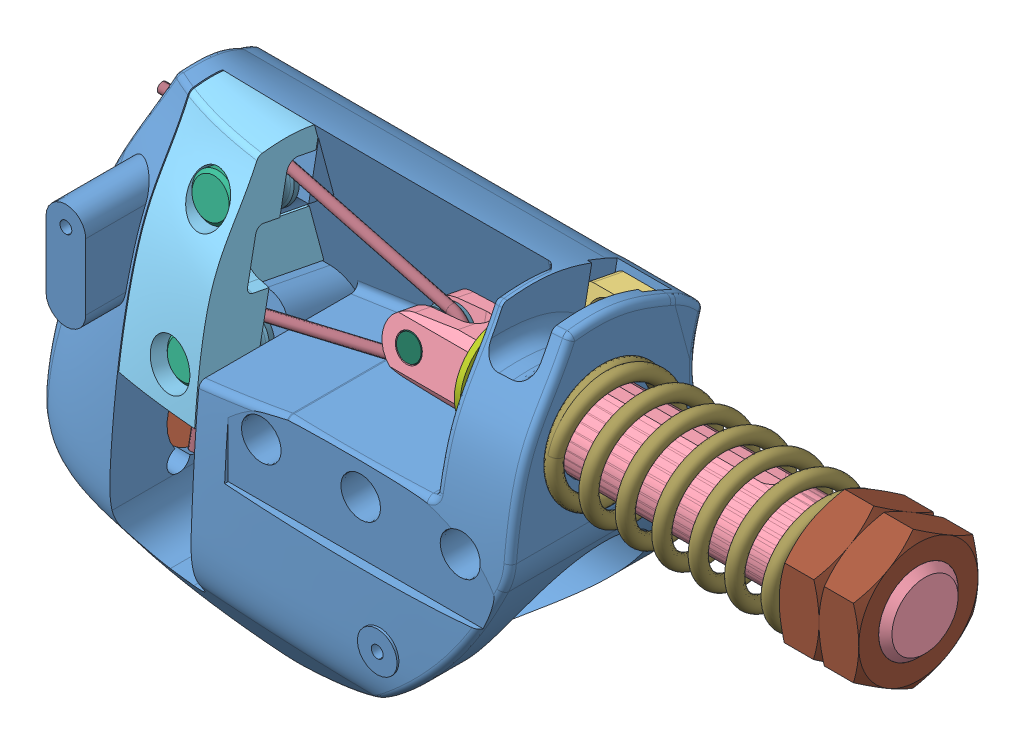
SolidWorks assembly a-motorträger-beine-links-v01, configuration 01. Lengths in mm.
Overall size (130.38 65.2 41.74).
22 component instances, 15 part files, 71 mates.
Components (placement in the parent):
- p-halterreferenz-links-v04-1: p-halterreferenz-links-v04 [01] at (-8 0 0) x (0 0 -1) z (1 0 0) size (41.74 65.2 84.36)
- z-jfm-0608-06-v01-1: z-jfm-0608-06-v01 [01] at (-23.3 0 0) x (-1 0 0) z (0 0 -1) size (6 12 12)
- z-induktiv-sensor-v01-1: z-induktiv-sensor-v01 [01] at (37 21.9082 -7.6275) x (-1 0 0) z (0 0.190809 0.981627) size (8 16 4.7)
- z-induktiv-sensor-v01-2: z-induktiv-sensor-v01 [01] at (-25.5 8.63 4) x (0 0 -1) z (-1 0 0) size (8 16 4.7)
- p-federstössel-v01-1: p-federstössel-v01 [01] at (77.9 27.8 1.72) x (-1 0 0) z (0 -0.190809 -0.981627) size (77 12 12)
- p-halterdeckel-links-v02-1: p-halterdeckel-links-v02 [01] at (-8 0 0) x (0 0 -1) z (1 0 0) size (28.27 33.45 14.71)
- z-passschraube-misumi-4-v01-1: z-passschraube-misumi-4-v01 [01] at (-13.1 35.2829 8.5672) x (0 -0.190809 -0.981627) z (-0.839411 0.533511 -0.103704) size (18 6.5 6.5)
- z-passschraube-misumi-4-v01-2: z-passschraube-misumi-4-v01 [01] at (-13.1 16.1412 12.288) x (0 -0.190809 -0.981627) z (-0.58333 -0.797312 0.154982) size (18 6.5 6.5)
- Lock washer DIN 6799 - 7-8: Lock washer DIN 6799 - 7 [Lock washer DIN 6799 - 7] at (24 27.8 1.72) x (0 0 1) z (-1 0 0) size (14.3 11.94 0.9)
- Hexagon Nut ISO 4032 - M2.5 - W - N-13: Hexagon Nut ISO 4032 - M2.5 - W - N [Hexagon Nut ISO 4032 - M2.5 - W - N] at (-13.1 31.8991 -8.8409) x (0.5 0.850114 -0.165245) z (0 -0.190809 -0.981627) size (5 5.77 2)
- Hexagon Nut ISO 4032 - M2.5 - W - N-14: Hexagon Nut ISO 4032 - M2.5 - W - N [Hexagon Nut ISO 4032 - M2.5 - W - N] at (-13.1 12.7574 -5.1202) x (0.5 0.850114 -0.165245) z (0 -0.190809 -0.981627) size (5 5.77 2)
- DIN 7991 - M3 x 8 --- 4.8C-13: DIN 7991 - M3 x 8 --- 4.8C [DIN 7991 - M3 x 8 --- 4.8C] at (-30.15 20.63 0) size (8 5.7 5.7)
- DIN 7991 - M3 x 8 --- 4.8C-14: DIN 7991 - M3 x 8 --- 4.8C [DIN 7991 - M3 x 8 --- 4.8C] at (33 34.5749 -5.3527) x (0 -0.190809 -0.981627) z (-0.981627 -0.187303 0.036408) size (8 5.7 5.7)
- p-oese-v01-1: p-oese-v01 [01] at (-25.5 37.4 0) size (3.5 4 4)
- Hexagon Thin Nut ISO 4035 - M12 - N-13: Hexagon Thin Nut ISO 4035 - M12 - N [Hexagon Thin Nut ISO 4035 - M12 - N] at (74.9 27.8 1.72) x (0 -0.006521 -0.999979) z (-1 0 0) size (18 20.78 6)
- Hexagon Thin Nut ISO 4035 - M12 - N-14: Hexagon Thin Nut ISO 4035 - M12 - N [Hexagon Thin Nut ISO 4035 - M12 - N] at (80.9 27.8 1.72) x (0 0 1) z (-1 0 0) size (18 20.78 6)
- z-feder-febrotec-v01-1: z-feder-febrotec-v01 [01] at (40 27.5466 1.7693) x (1 0 0) z (0 -0.190809 -0.981627) size (40.25 20.98 20.5)
- p-seil-v02-1: p-seil-v02 [01] at (-16.85 -0.1381 7.1506) x (-1 0 0) z (0 -0.190809 -0.981627) size (48.5 39 1.5)
- p-umlenkpulley-v06-1: p-umlenkpulley-v06 [01] at (-13.1 33.728 0.5677) x (0 -0.190809 -0.981627) z (-0.981627 -0.187303 0.036408) size (3.6 7.15 7.15)
- p-umlenkpulley-v06-4: p-umlenkpulley-v06 [01] at (-13.1 14.5863 4.2885) x (0 -0.190809 -0.981627) z (-0.997632 -0.067518 0.013124) size (3.6 7.15 7.15)
- p-umlenkpulley-v06-3: p-umlenkpulley-v06 [01] at (14.9 27.8 1.72) x (0 -0.190809 -0.981627) z (-0.981627 -0.187303 0.036408) size (3.6 7.15 7.15)
- Parallel Pin ISO 2338 - 4 h6 x 10 - St-8: Parallel Pin ISO 2338 - 4 h6 x 10 - St [Parallel Pin ISO 2338 - 4 h6 x 10 - St] at (14.9 28.754 6.6281) x (0 -0.190809 -0.981627) z (-0.981627 -0.187303 0.036408) size (10 4 4)
Mates (geometry in assembly coordinates):
- Deckungsgleich4: coincident anti-aligned: plane of z-jfm-0608-06-v01-1 through (-23.3 0 0) normal (0 0 -1); plane of assembly through (0 0 0) normal (0 0 1)
- Deckungsgleich22: coincident aligned: plane of p-halterreferenz-links-v04-1; plane of assembly through (0 0 0) normal (0 1 0)
- Deckungsgleich23: coincident anti-aligned: plane of p-halterreferenz-links-v04-1 through (-8 0 0) normal (0 0 -1); plane of assembly through (0 0 0) normal (0 0 1)
- Konzentrisch3: concentric aligned: cylinder of z-induktiv-sensor-v01-2 through (-30.2 20.63 0) axis (-1 0 0) radius 1.55; cylinder of p-halterreferenz-links-v04-1 through (38.3169 20.63 0) axis (-1 0 0) radius 1.23
- Deckungsgleich25: coincident aligned: plane of z-induktiv-sensor-v01-2; plane of p-halterreferenz-links-v04-1 through (-8 0 0) normal (0 0 -1)
- Deckungsgleich26: coincident anti-aligned: plane of z-induktiv-sensor-v01-2 through (-25.5 8.63 4) normal (1 0 0); plane of p-halterreferenz-links-v04-1 through (-25.5 0 0) normal (-1 0 0)
- Konzentrisch4: concentric aligned: cylinder of p-halterreferenz-links-v04-1 through (-39.3597 27.8 1.72) axis (1 0 0) radius 6.125; cylinder of p-federstössel-v01-1 through (77.9 27.8 1.72) axis (1 0 0) radius 6
- Parallel3: parallel anti-aligned: plane of p-halterreferenz-links-v04-1 through (-39.3597 33.8847 2.4219) normal (0 0.190809 0.981627); plane of p-federstössel-v01-1 through (65.9 35.5438 2.2522) normal (0 -0.190809 -0.981627)
- Deckungsgleich32: coincident aligned: plane of p-halterreferenz-links-v04-1; plane of p-halterdeckel-links-v02-1
- Deckungsgleich33: coincident anti-aligned: plane of p-halterdeckel-links-v02-1 through (-8 0 0) normal (0 0 -1); plane of assembly through (0 0 0) normal (0 0 1)
- Deckungsgleich34: coincident aligned: plane of p-halterdeckel-links-v02-1 through (-8 0 0) normal (1 0 0); plane of p-halterreferenz-links-v04-1 through (-8 0 0) normal (1 0 0)
- Konzentrisch5: concentric aligned: cylinder of p-halterreferenz-links-v04-1 through (-13.1 32.6624 -4.9144) axis (0 0.190809 0.981627) radius 2.075; cylinder of z-passschraube-misumi-4-v01-1 through (-13.1 35.2829 8.5672) axis (0 0.190809 0.981627) radius 2
- Deckungsgleich35: coincident anti-aligned: plane of p-halterdeckel-links-v02-1 through (-13.1 2.3168 11.919) normal (0 0.190809 0.981627); plane of z-passschraube-misumi-4-v01-1 through (-14.8664 32.0326 6.1429) normal (0 -0.190809 -0.981627)
- Konzentrisch7: concentric aligned: cylinder of p-halterreferenz-links-v04-1 through (-13.1 13.5207 -1.1937) axis (0 0.190809 0.981627) radius 2.075; cylinder of z-passschraube-misumi-4-v01-2 through (-13.1 16.1412 12.288) axis (0 0.190809 0.981627) radius 2
- Deckungsgleich36: coincident anti-aligned: plane of p-halterdeckel-links-v02-1 through (-13.1 2.3168 11.919) normal (0 0.190809 0.981627); plane of z-passschraube-misumi-4-v01-2 through (-10.4602 13.7078 9.7048) normal (0 -0.190809 -0.981627)
- Konzentrisch9: concentric anti-aligned: cylinder of p-federstössel-v01-1 through (77.9 27.8 1.72) axis (1 0 0) radius 3.5; cylinder of Lock washer DIN 6799 - 7-8 through (24.9 27.8 1.72) axis (-1 0 0) radius 3.5
- Deckungsgleich40: coincident anti-aligned: plane of p-federstössel-v01-1 through (24.9 33.6898 0.5751) normal (-1 0 0); plane of Lock washer DIN 6799 - 7-8 through (24.9 27.8 1.72) normal (1 0 0)
- Konzentrisch10: concentric anti-aligned: cylinder of p-halterreferenz-links-v04-1 through (-13.1 27.2158 -32.9346) axis (0 0.190809 0.981627) radius 1.5; cylinder of Hexagon Nut ISO 4032 - M2.5 - W - N-13 through (-13.1 32.2808 -6.8777) axis (0 -0.190809 -0.981627) radius 1.025
- Parallel4: parallel anti-aligned: plane of p-halterreferenz-links-v04-1 through (-10.5 25.7423 -32.6482) normal (-0.5 0.850114 -0.165245); plane of Hexagon Nut ISO 4032 - M2.5 - W - N-13 through (-10.6 30.8639 -6.6023) normal (0.5 -0.850114 0.165245)
- Deckungsgleich42: coincident anti-aligned: plane of p-halterreferenz-links-v04-1 through (-8 -0.1129 -0.581) normal (0 -0.190809 -0.981627); plane of Hexagon Nut ISO 4032 - M2.5 - W - N-13 through (-10.6 30.8639 -6.6023) normal (0 0.190809 0.981627)
- Konzentrisch11: concentric anti-aligned: cylinder of p-halterreferenz-links-v04-1 through (-13.1 8.0741 -29.2138) axis (0 0.190809 0.981627) radius 1.5; cylinder of Hexagon Nut ISO 4032 - M2.5 - W - N-14 through (-13.1 13.139 -3.1569) axis (0 -0.190809 -0.981627) radius 1.025
- Parallel5: parallel anti-aligned: plane of p-halterreferenz-links-v04-1 through (-10.5 6.6006 -28.9274) normal (-0.5 0.850114 -0.165245); plane of Hexagon Nut ISO 4032 - M2.5 - W - N-14 through (-10.6 11.7222 -2.8815) normal (0.5 -0.850114 0.165245)
- Deckungsgleich44: coincident anti-aligned: plane of p-halterreferenz-links-v04-1 through (-8 -0.1129 -0.581) normal (0 -0.190809 -0.981627); plane of Hexagon Nut ISO 4032 - M2.5 - W - N-14 through (-10.6 11.7222 -2.8815) normal (0 0.190809 0.981627)
- Konzentrisch12: concentric aligned: cylinder of z-induktiv-sensor-v01-2 through (-30.2 20.63 0) axis (-1 0 0) radius 1.55; cylinder of DIN 7991 - M3 x 8 --- 4.8C-13 through (-30.15 20.63 0) axis (-1 0 0) radius 1.5
- Deckungsgleich45: coincident aligned: cone of z-induktiv-sensor-v01-2 through (-28.5 20.63 0) axis (1 0 0); cone of DIN 7991 - M3 x 8 --- 4.8C-13 through (-29.8 20.63 0) axis (1 0 0)
- Konzentrisch14: concentric aligned: cylinder of z-induktiv-sensor-v01-1 through (33 34.5845 -5.3036) axis (0 0.190809 0.981627) radius 1.55; cylinder of DIN 7991 - M3 x 8 --- 4.8C-14 through (33 34.5749 -5.3527) axis (0 0.190809 0.981627) radius 1.5
- Deckungsgleich46: coincident aligned: cone of z-induktiv-sensor-v01-1 through (33 34.2601 -6.9724) axis (0 -0.190809 -0.981627); cone of DIN 7991 - M3 x 8 --- 4.8C-14 through (33 34.5082 -5.6962) axis (0 -0.190809 -0.981627)
- Konzentrisch16: concentric anti-aligned: cylinder of p-halterreferenz-links-v04-1 through (-21.3635 37.4 0) axis (1 0 0) radius 1; cylinder of p-oese-v01-1 through (-25.5 37.4 0) axis (-1 0 0) radius 2
- Deckungsgleich47: coincident anti-aligned: plane of p-halterreferenz-links-v04-1 through (-25.5 39.55 0) normal (1 0 0); plane of p-oese-v01-1 through (-25.5 39.4 0) normal (-1 0 0)
- Konzentrisch17: concentric anti-aligned: cylinder of p-federstössel-v01-1 through (77.9 27.8 1.72) axis (1 0 0) radius 6; cylinder of Hexagon Thin Nut ISO 4035 - M12 - N-13 through (80.9 27.8 1.72) axis (-1 0 0) radius 5.1
- Abstand16: distance = 7 mm aligned: plane of Hexagon Thin Nut ISO 4035 - M12 - N-13 through (80.9 17.4079 1.7878) normal (1 0 0); plane of p-federstössel-v01-1 through (87.9 33.6898 0.5751) normal (1 0 0)
- Konzentrisch19: concentric anti-aligned: cylinder of p-federstössel-v01-1 through (77.9 27.8 1.72) axis (1 0 0) radius 6; cylinder of Hexagon Thin Nut ISO 4035 - M12 - N-14 through (86.9 27.8 1.72) axis (-1 0 0) radius 5.1
- Deckungsgleich49: coincident anti-aligned: plane of Hexagon Thin Nut ISO 4035 - M12 - N-13 through (80.9 17.4079 1.7878) normal (1 0 0); plane of Hexagon Thin Nut ISO 4035 - M12 - N-14 through (80.9 38.1923 1.72) normal (-1 0 0)
- Deckungsgleich50: coincident aligned: plane of p-federstössel-v01-1 through (77.9 27.8 1.72) normal (0 -0.190809 -0.981627); plane of z-feder-febrotec-v01-1 through (40 27.5466 1.7693) normal (0 -0.190809 -0.981627)
- Abstand17: distance = 3 mm aligned: plane of z-feder-febrotec-v01-1; plane of p-halterreferenz-links-v04-1 through (37 0 0) normal (1 0 0)
- Konzentrisch20: concentric anti-aligned: cylinder of z-passschraube-misumi-4-v01-1 through (-13.1 35.2829 8.5672) axis (0 0.190809 0.981627) radius 2; cylinder of p-umlenkpulley-v06-1 through (-13.1 31.4085 -11.3649) axis (0 -0.190809 -0.981627) radius 2.075
- Deckungsgleich52: coincident aligned: plane of p-federstössel-v01-1 through (77.9 27.8 1.72) normal (0 -0.190809 -0.981627); plane of p-umlenkpulley-v06-1
- Konzentrisch21: concentric anti-aligned: cylinder of z-passschraube-misumi-4-v01-2 through (-13.1 16.1412 12.288) axis (0 0.190809 0.981627) radius 2; cylinder of p-umlenkpulley-v06-4 through (-13.1 12.2668 -7.6441) axis (0 -0.190809 -0.981627) radius 2.075
- Deckungsgleich53: coincident aligned: plane of p-umlenkpulley-v06-1 through (-12.4179 30.6266 3.0043) normal (0 0.190809 0.981627); plane of p-umlenkpulley-v06-4 through (-12.8541 11.4287 6.7359) normal (0 0.190809 0.981627)
- Konzentrisch22: concentric: cylinder of z-passschraube-misumi-4-v01-1 through (-13.1 35.2829 8.5672) axis (0 0.190809 0.981627) radius 2; point of p-seil-v02-1
- Konzentrisch23: concentric: cylinder of z-passschraube-misumi-4-v01-2 through (-13.1 16.1412 12.288) axis (0 0.190809 0.981627) radius 2; point of p-seil-v02-1
- Deckungsgleich57: coincident aligned: plane of p-seil-v02-1 through (-16.85 -0.1381 7.1506) normal (0 -0.190809 -0.981627); plane of p-umlenkpulley-v06-1
- Deckungsgleich59: coincident anti-aligned: plane of p-halterreferenz-links-v04-1 through (-8 0 0) normal (0 0 -1); plane of assembly through (0 0 0) normal (0 0 1)
- Abstand18: distance = 8 mm aligned: plane of assembly through (0 0 0) normal (1 0 0); plane of p-halterreferenz-links-v04-1 through (-8 0 0) normal (1 0 0)
- Konzentrisch24: concentric aligned: cylinder of p-halterreferenz-links-v04-1 through (0 0 0) axis (1 0 0) radius 4.075; cylinder of z-jfm-0608-06-v01-1 through (-23.3 0 0) axis (1 0 0) radius 4
- Deckungsgleich64: coincident anti-aligned: plane of p-halterreferenz-links-v04-1 through (-24.3 6.25 0) normal (1 0 0); plane of z-jfm-0608-06-v01-1 through (-24.3 6 0) normal (-1 0 0)
- Parallel6: parallel aligned: plane of z-jfm-0608-06-v01-1; plane of assembly through (0 0 0) normal (0 1 0)
- Konzentrisch25: concentric aligned: cylinder of p-halterreferenz-links-v04-1 through (33 29.1408 -33.3088) axis (0 0.190809 0.981627) radius 1.23; cylinder of z-induktiv-sensor-v01-1 through (33 34.5845 -5.3036) axis (0 0.190809 0.981627) radius 1.55
- Deckungsgleich65: coincident anti-aligned: plane of p-halterreferenz-links-v04-1 through (28.85 41.4425 -11.4246) normal (0 0.190809 0.981627); plane of z-induktiv-sensor-v01-1 through (37 21.9082 -7.6275) normal (0 -0.190809 -0.981627)
- Parallel7: parallel aligned: plane of p-halterreferenz-links-v04-1 through (37.15 0 0) normal (-1 0 0); plane of z-induktiv-sensor-v01-1 through (29 22.805 -3.0139) normal (-1 0 0)
- Konzentrisch26: concentric aligned: cylinder of p-federstössel-v01-1 through (14.9 29.1357 8.5914) axis (0 -0.190809 -0.981627) radius 2; cylinder of p-umlenkpulley-v06-3 through (14.9 25.4805 -10.2126) axis (0 -0.190809 -0.981627) radius 2.075
- Deckungsgleich69: coincident aligned: plane of p-federstössel-v01-1 through (77.9 27.8 1.72) normal (0 -0.190809 -0.981627); plane of p-umlenkpulley-v06-3
- Konzentrisch27: concentric anti-aligned: cylinder of p-federstössel-v01-1 through (14.9 29.1357 8.5914) axis (0 -0.190809 -0.981627) radius 2; cylinder of Parallel Pin ISO 2338 - 4 h6 x 10 - St-8 through (14.9 29.9657 12.8615) axis (0 0.190809 0.981627) radius 2
- Abstand19: distance = 5 mm anti-aligned: plane of p-federstössel-v01-1 through (77.9 27.8 1.72) normal (0 -0.190809 -0.981627); plane of Parallel Pin ISO 2338 - 4 h6 x 10 - St-8 through (15.2494 26.9895 6.9711) normal (0 0.190809 0.981627)
- Abstand20: distance = 28 mm aligned: plane of p-federstössel-v01-1; plane of p-halterreferenz-links-v04-1 through (-13.1 0 0) normal (-1 0 0)
- Konzentrisch192: concentric aligned: cylinder of p-halterdeckel-links-v02-1 through (-13.1 36.3949 14.2879) axis (0 0.190809 0.981627) radius 2; cylinder of z-passschraube-misumi-4-v01-1 through (-13.1 35.2829 8.5672) axis (0 0.190809 0.981627) radius 2
- Deckungsgleich159: coincident anti-aligned: plane of p-halterdeckel-links-v02-1 through (-13.1 2.3168 11.919) normal (0 0.190809 0.981627); plane of z-passschraube-misumi-4-v01-1 through (-14.8664 37.3885 5.1018) normal (0 -0.190809 -0.981627)
- Konzentrisch193: concentric aligned: cylinder of p-halterdeckel-links-v02-1 through (-13.1 17.4154 18.843) axis (0 0.190809 0.981627) radius 2; cylinder of z-passschraube-misumi-4-v01-2 through (-13.1 16.1412 12.288) axis (0 0.190809 0.981627) radius 2
- Deckungsgleich160: coincident anti-aligned: plane of p-halterdeckel-links-v02-1 through (-13.1 2.3168 11.919) normal (0 0.190809 0.981627); plane of z-passschraube-misumi-4-v01-2 through (-10.4602 17.4298 8.9813) normal (0 -0.190809 -0.981627)
- Konzentrisch194: concentric aligned: cylinder of p-federstössel-v01-1 through (71.9 27.8 1.72) axis (1 0 0) radius 3.5; cylinder of Lock washer DIN 6799 - 7-8 through (18 27.8 1.72) axis (1 0 0) radius 3.5
- Konzentrisch197: concentric aligned: cylinder of z-induktiv-sensor-v01-2 through (-30.2 20.63 0) axis (-1 0 0) radius 1.55; cylinder of DIN 7991 - M3 x 8 --- 4.8C-13 through (-30.15 20.63 0) axis (-1 0 0) radius 1.5
- Deckungsgleich163: coincident aligned: cone of z-induktiv-sensor-v01-2 through (-28.5 20.63 0) axis (1 0 0); cone of DIN 7991 - M3 x 8 --- 4.8C-13 through (-29.8 20.63 0) axis (1 0 0)
- Konzentrisch198: concentric aligned: cylinder of z-induktiv-sensor-v01-1 through (33 34.5845 -5.3036) axis (0 0.190809 0.981627) radius 1.55; cylinder of DIN 7991 - M3 x 8 --- 4.8C-14 through (33 34.5749 -5.3527) axis (0 0.190809 0.981627) radius 1.5
- Deckungsgleich164: coincident aligned: cone of z-induktiv-sensor-v01-1 through (33 34.2601 -6.9724) axis (0 -0.190809 -0.981627); cone of DIN 7991 - M3 x 8 --- 4.8C-14 through (33 34.5082 -5.6962) axis (0 -0.190809 -0.981627)
- Konzentrisch200: concentric aligned: cylinder of p-federstössel-v01-1 through (71.9 27.8 1.72) axis (1 0 0) radius 6; cylinder of Hexagon Thin Nut ISO 4035 - M12 - N-13 through (67.8963 27.8 1.72) axis (1 0 0) radius 5.1
- Konzentrisch201: concentric aligned: cylinder of p-federstössel-v01-1 through (71.9 27.8 1.72) axis (1 0 0) radius 6; cylinder of Hexagon Thin Nut ISO 4035 - M12 - N-14 through (73.8963 27.8 1.72) axis (1 0 0) radius 5.1
- Konzentrisch202: concentric anti-aligned: cylinder of z-passschraube-misumi-4-v01-1 through (-13.1 35.2829 8.5672) axis (0 0.190809 0.981627) radius 2; cylinder of p-umlenkpulley-v06-1 through (-13.1 31.4085 -11.3649) axis (0 -0.190809 -0.981627) radius 2
- Konzentrisch203: concentric anti-aligned: cylinder of z-passschraube-misumi-4-v01-2 through (-13.1 16.1412 12.288) axis (0 0.190809 0.981627) radius 2; cylinder of p-umlenkpulley-v06-4 through (-13.1 12.2668 -7.6441) axis (0 -0.190809 -0.981627) radius 2
- Deckungsgleich166: coincident aligned: plane of p-umlenkpulley-v06-1 through (-12.4322 37.444 1.6791) normal (0 0.190809 0.981627); plane of p-umlenkpulley-v06-4 through (-12.8593 18.3573 5.3892) normal (0 0.190809 0.981627)
- Konzentrisch206: concentric aligned: cylinder of p-federstössel-v01-1 through (8.9 29.1357 8.5914) axis (0 -0.190809 -0.981627) radius 2; cylinder of p-umlenkpulley-v06-3 through (8.9 25.4805 -10.2126) axis (0 -0.190809 -0.981627) radius 2
- Konzentrisch207: concentric anti-aligned: cylinder of p-federstössel-v01-1 through (8.9 29.1357 8.5914) axis (0 -0.190809 -0.981627) radius 2; cylinder of Parallel Pin ISO 2338 - 4 h6 x 10 - St-8 through (8.9 29.9657 12.8615) axis (0 0.190809 0.981627) radius 2
